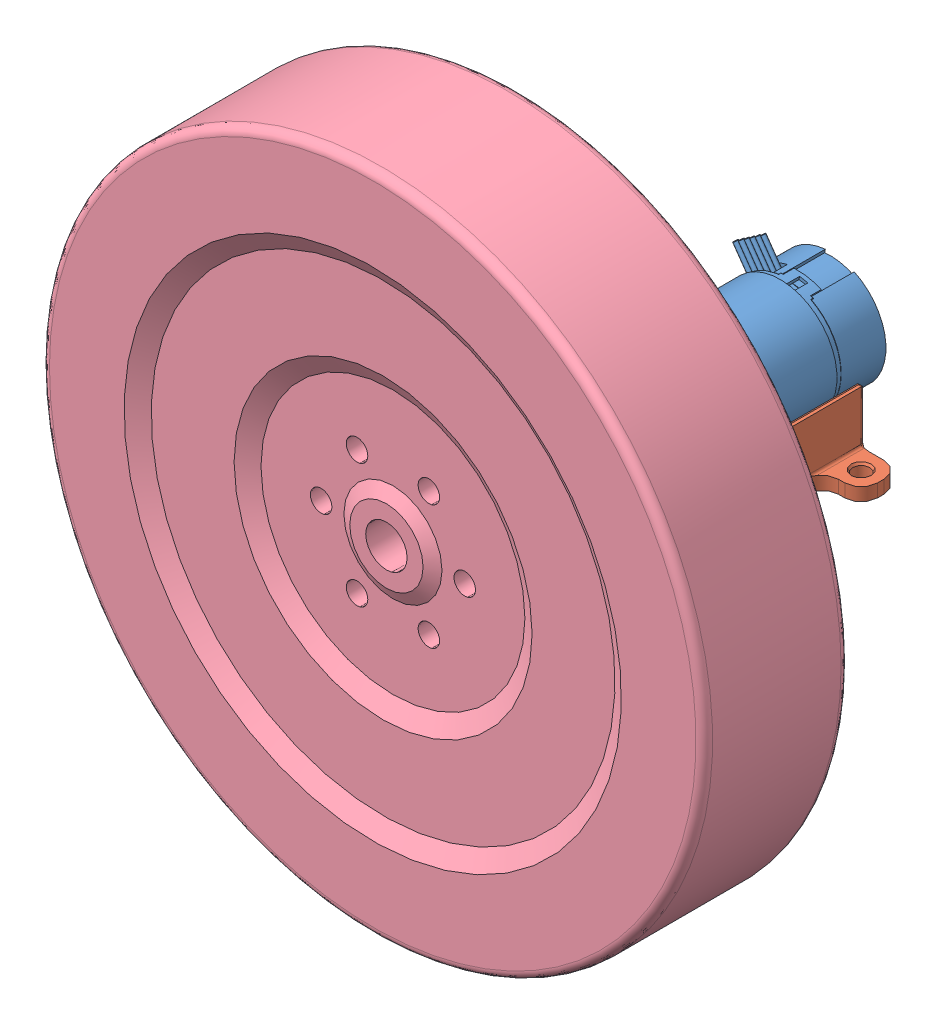
SolidWorks assembly assem_wheelDrive, configuration Default. Lengths in mm.
Overall size (277.58 277.58 140.26).
6 component instances, 6 part files, 17 mates.
Components (placement in the parent):
- gearmotor_Pololu_30-1-1: gearmotor_Pololu_30-1 [Default] at (19.925 0 -19.925) x (-1 0 0) z (0 0 1) size (36.88 41.23 90.1)
- motorMount-1: motorMount [Default] at origin size (61 43.5 64)
- hub_v2-1: hub_v2 [Default] at (0 7 34) x (0 -1 0) z (1 0 0) size (66 44 66)
- wheel-1: wheel [Default] at (0 7 49.934) x (0 0 -1) z (0.5 0.866025 0) size (44.45 203.2 203.2)
- 93365A142_HEAT-SET INSERTS FOR PLASTICS-1: 93365A142_HEAT-SET INSERTS FOR PLASTICS [93365A142] at (0 -8 19) x (1 0 0) z (0 0 -1) size (6.35 8.46 6.35)
- 91772A197_18-8 SS PAN HEAD PHILLIPS MACHINE SCREW-1: 91772A197_18-8 SS PAN HEAD PHILLIPS MACHINE SCREW [91772A197] at (0 4.6 19) x (-0.300305 0 -0.953843) z (0 -1 0) size (8.18 8.18 22.32)
Mates (geometry in assembly coordinates):
- Concentric1: concentric: cylinder of gearmotor_Pololu_30-1-1 through (0 7 6) axis (0 0 -1) radius 6; cylinder of motorMount-1 through (0 7 4) axis (0 0 -1) radius 6.25
- Concentric2: concentric: circle of gearmotor_Pololu_30-1-1; circle of motorMount-1
- Coincident1: coincident: plane of gearmotor_Pololu_30-1-1 through (0 0 0) normal (0 0 1); plane of motorMount-1 through (0 0 0) normal (0 0 -1)
- Concentric3: concentric: cylinder of gearmotor_Pololu_30-1-1 through (0 7 22) axis (0 0 -1) radius 3; cylinder of ? through (0 7 30) axis (0 0 1) radius 3
- Coincident2: coincident: plane of gearmotor_Pololu_30-1-1 through (0 7 22) normal (0 0 1); plane of ? through (3.05 7 22) normal (0 0 -1)
- Parallel1: parallel: plane of gearmotor_Pololu_30-1-1 through (1.8 4.6 10) normal (0 -1 0); plane of ? through (0 -3 18) normal (0 -1 0)
- Coincident3: coincident: plane of gearmotor_Pololu_30-1-1 through (0 7 6) normal (0 0 1); plane of ? through (3 7 6) normal (0 0 -1)
- Concentric5: concentric: circle of hub_v2-1; circle of gearmotor_Pololu_30-1-1
- Parallel4: parallel: plane of gearmotor_Pololu_30-1-1 through (1.8 4.6 10) normal (0 -1 0); plane of hub_v2-1 through (-1.6583 4.5 34) normal (0 1 0)
- Coincident8: coincident: plane of gearmotor_Pololu_30-1-1 through (0 7 10) normal (0 0 1); plane of hub_v2-1 through (3 7 10) normal (0 0 -1)
- Concentric6: concentric: cylinder of hub_v2-1 through (0 7 54) axis (0 0 -1) radius 6.45; cylinder of wheel-1 through (0 7 49.934) axis (0 0 1) radius 6.35
- Coincident9: coincident: plane of hub_v2-1 through (0 7 31.9) normal (0 0 1); plane of wheel-1 through (5.6197 16.7337 31.9) normal (0 0 -1)
- Concentric7: concentric: cylinder of hub_v2-1 through (11 26.0526 10) axis (0 0 1) radius 3.302; cylinder of wheel-1 through (11 26.0526 72.159) axis (0 0 -1) radius 3.3
- Concentric8: concentric: circle of hub_v2-1; circle of 93365A142_HEAT-SET INSERTS FOR PLASTICS-1
- Coincident10: coincident: plane of hub_v2-1 through (0 -8 19) normal (0 -1 0); plane of 93365A142_HEAT-SET INSERTS FOR PLASTICS-1 through (0 -8 19) normal (0 -1 0)
- Concentric9: concentric: circle of 93365A142_HEAT-SET INSERTS FOR PLASTICS-1; cylinder of 91772A197_18-8 SS PAN HEAD PHILLIPS MACHINE SCREW-1 through (0 4.6 19) axis (0 1 0) radius 4.0894
- Coincident11: coincident: plane of gearmotor_Pololu_30-1-1 through (1.8 4.6 10) normal (0 -1 0); plane of 91772A197_18-8 SS PAN HEAD PHILLIPS MACHINE SCREW-1 through (0 4.6 19) normal (0 1 0)
